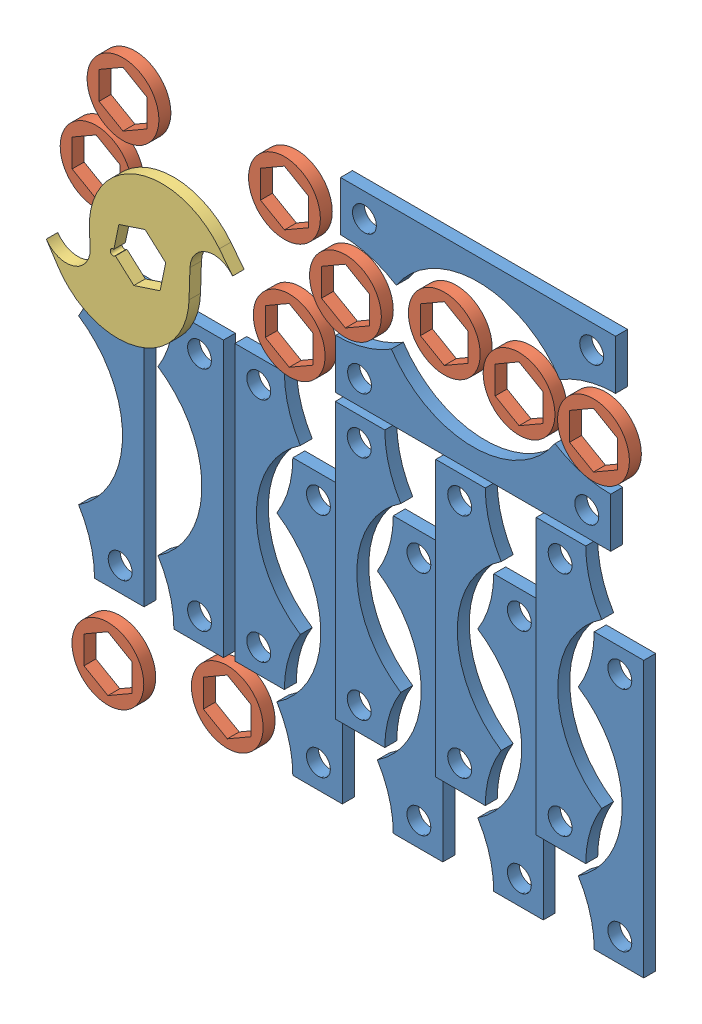
SolidWorks assembly Flat_Pattern_1, configuration Default. Lengths in mm.
Overall size (304.8 304.8 43.18).
23 component instances, 3 part files, 14 mates.
Components (placement in the parent):
- Spacer_1-1: Spacer_1 [Default] at (-19.05 73.025 -3.175) size (34.77 146.05 6.35)
- Spacer_1-3: Spacer_1 [Default] at (-31.6908 116.5616 3.175) x (-1 0 0) z (0 0 -1) size (34.77 146.05 6.35)
- Spacer_1-4: Spacer_1 [Default] at (-72.39 73.025 -3.175) size (34.77 146.05 6.35)
- Spacer_1-5: Spacer_1 [Default] at (-125.73 73.025 -3.175) size (34.77 146.05 6.35)
- Spacer_1-6: Spacer_1 [Default] at (-179.07 73.025 -3.175) size (34.77 146.05 6.35)
- Spacer_1-8: Spacer_1 [Default] at (-85.0308 116.5616 3.175) x (-1 0 0) z (0 0 -1) size (34.77 146.05 6.35)
- Spacer_1-9: Spacer_1 [Default] at (-138.3708 116.5616 3.175) x (-1 0 0) z (0 0 -1) size (34.77 146.05 6.35)
- Spacer_1-10: Spacer_1 [Default] at (-191.7108 116.5616 3.175) x (-1 0 0) z (0 0 -1) size (34.77 146.05 6.35)
- Spacer_1-12: Spacer_1 [Default] at (-84.2156 212.7971 3.175) x (0 -1 0) z (0 0 1) size (34.77 146.05 6.35)
- Hex_Spacer-1: Hex_Spacer [Default] at (-217.9474 17.2506 0) size (38.1 38.1 6.35)
- Hex_Spacer-2: Hex_Spacer [Default] at (-59.857 241.8623 3.175) size (38.1 38.1 6.35)
- Hex_Spacer-4: Hex_Spacer [Default] at (-105.8808 243.3754 -3.175) size (38.1 38.1 6.35)
- Spacer_1-14: Spacer_1 [Default] at (-81.6167 274.8989 3.175) x (0 1 0) z (0 0 1) size (34.77 146.05 6.35)
- Hex_Spacer-5: Hex_Spacer [Default] at (-17.1679 243.4732 6.35) size (38.1 38.1 6.35)
- Hex_Spacer-6: Hex_Spacer [Default] at (-148.8599 243.8759 6.35) size (38.1 38.1 6.35)
- Hex_Spacer-7: Hex_Spacer [Default] at (-178.7033 210.8857 6.35) size (38.1 38.1 6.35)
- Hex_Spacer-10: Hex_Spacer [Default] at (-263.7871 278.5336 9.525) size (38.1 38.1 6.35)
- Hex_Spacer-11: Hex_Spacer [Default] at (-268.6303 18.1484 12.7) size (38.1 38.1 6.35)
- Hex_Spacer-12: Hex_Spacer [Default] at (-278.0692 240.3003 9.525) size (38.1 38.1 6.35)
- Hex_Spacer-13: Hex_Spacer [Default] at (-174.897 279.1321 12.7) size (38.1 38.1 6.35)
- Spacer_1-15: Spacer_1 [Default] at (-235.8551 115.0764 3.175) size (34.77 146.05 6.35)
- Spacer_1-16: Spacer_1 [Default] at (-276.8363 118.5006 4.3233) x (1 0 0) z (0 0 -1) size (34.77 146.05 6.35)
- 2Tooth_Cutter_V1-1: 2Tooth_Cutter_V1 [Default] at (-230.8874 234.2322 33.7857) x (-0.31184 0.950135 0) z (0 0 1) size (75.28 104.14 6.1)
Mates (geometry in assembly coordinates):
- Coincident1: coincident: plane of Spacer_1-1 through (-19.05 73.025 0) normal (0 0 1); plane of assembly through (0 0 0) normal (0 0 1)
- Coincident2: coincident: plane of Spacer_1-1 through (0 73.025 0) normal (1 0 0); plane of assembly through (0 0 0) normal (1 0 0)
- Coincident3: coincident: plane of Spacer_1-1 through (-19.05 0 0) normal (0 -1 0); plane of assembly through (0 0 0) normal (0 1 0)
- Parallel1: parallel: line of Spacer_1-3 through (146.05 -50.7408 43.5366) axis (0 0 1); plane of assembly
- Parallel2: parallel: line of Spacer_1-3 through (-24.4447 43.5366 0) axis (-1 0 0); plane of assembly
- Coincident8: coincident: plane of Spacer_1-3 through (-31.6908 116.5616 0) normal (0 0 -1); plane of assembly through (0 0 0) normal (0 0 1)
- Coincident9: coincident: plane of Spacer_1-12 through (-84.2156 212.7971 0) normal (0 0 -1); plane of assembly through (0 0 0) normal (0 0 1)
- Parallel3: parallel: line of Spacer_1-12 through (-157.2406 220.0433 0) axis (0 -1 0); plane of assembly
- Parallel4: parallel: line of Spacer_1-14 through (-8.5917 267.6528 0) axis (0 1 0); line of assembly
- Coincident14: coincident: plane of Spacer_1-12 through (-84.2156 212.7971 0) normal (0 0 -1); plane of Spacer_1-14 through (-81.6167 274.8989 0) normal (0 0 -1)
- Parallel6: parallel: line of Spacer_1-1 through (0 0 -6.35) axis (0 1 0); plane of Hex_Spacer-13 through (-174.897 279.1321 9.525) normal (0 0 -1)
- Parallel7: parallel: line of Spacer_1-16 through (-284.0824 45.4756 7.4983) axis (1 0 0); line of assembly
- Parallel8: parallel: plane of Spacer_1-1 through (-19.05 73.025 -6.35) normal (0 0 -1); plane of Spacer_1-16 through (-276.8363 118.5006 1.1483) normal (0 0 -1)
- Parallel9: parallel: plane of Spacer_1-14 through (-81.6167 274.8989 0) normal (0 0 -1); plane of 2Tooth_Cutter_V1-1 through (-230.8874 234.2322 30.7377) normal (0 0 -1)
